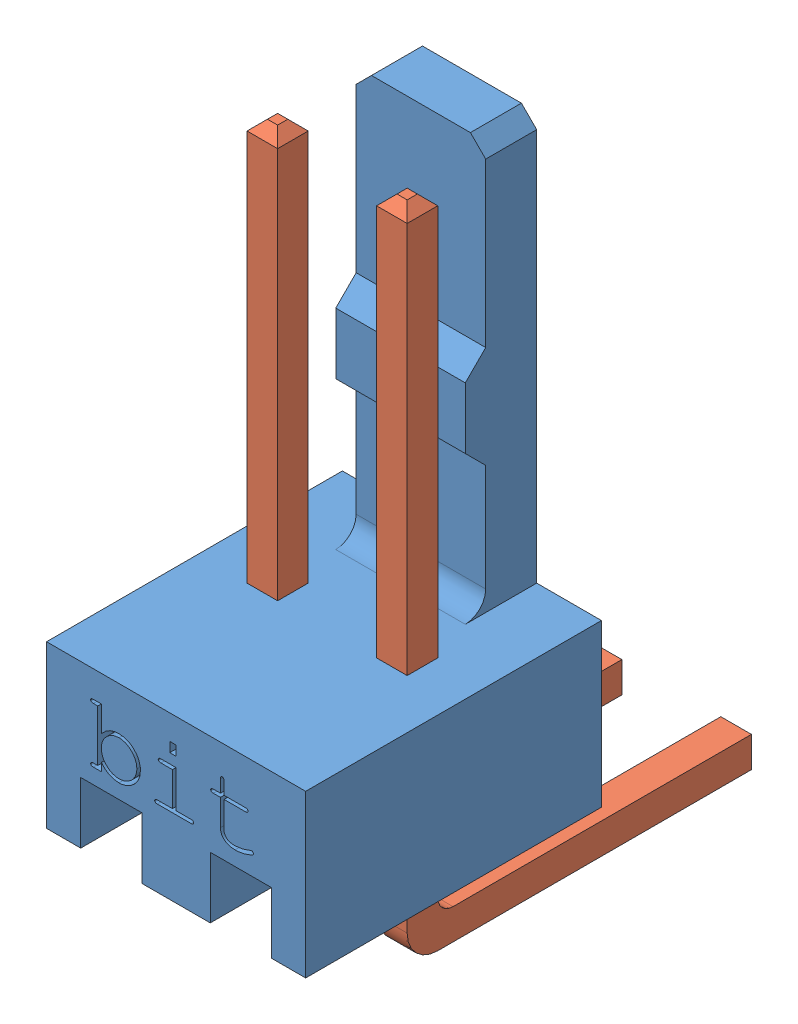
SolidWorks assembly Molex-2.54-2pin-angle, configuration Default. Lengths in mm.
Overall size (5.08 12.97 9.91).
4 component instances, 2 part files, 0 mates.
Components (placement in the parent):
- Molex-2.54-2pin-angle.STEP-1: Molex-2.54-2pin-angle.STEP [Default] at origin size (5.08 12.97 9.91)
  - Pieza2.STEP-1: Pieza2.STEP [Default] at (-1.0211 -6.362 11.17) size (5.08 11.17 5.8)
  - pin_90.STEP-1: pin_90.STEP [Default] at (-2.5911 -7.5649 10.51) x (0 0 1) z (0 1 0) size (6.95 0.6 12.85)
  - pin_90.STEP-2: pin_90.STEP [Default] at (-0.0511 -7.5649 10.51) x (0 0 1) z (0 1 0) size (6.95 0.6 12.85)
